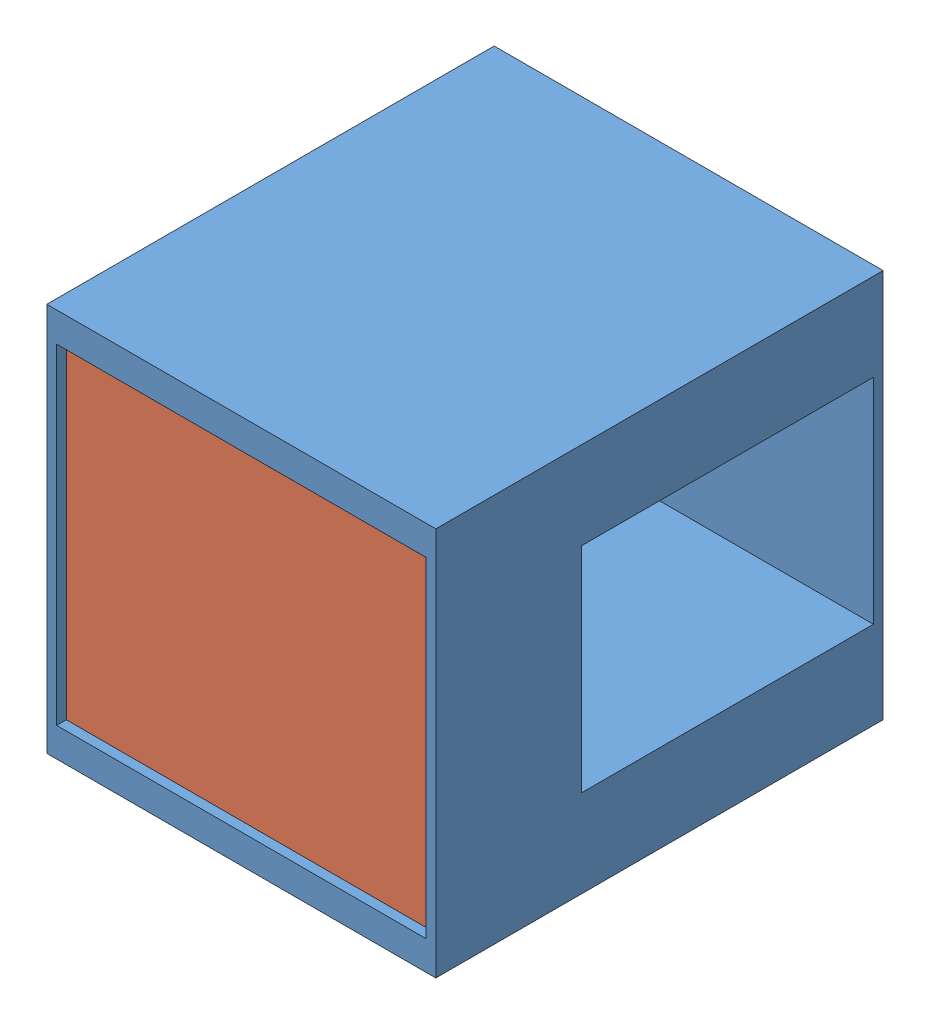
SolidWorks assembly Enclosure assem 1, configuration Default. Lengths in mm.
Overall size (101.6 101.6 116.84).
2 component instances, 2 part files, 3 mates.
Components (placement in the parent):
- Enclosure 1-1: Enclosure 1 [Default] at (-47.675 110.0742 53.7843) size (101.6 101.6 116.84)
- Enclosure top 1-1: Enclosure top 1 [Default] at (51.2011 107.5342 168.0843) x (0 -1 0) z (1 0 0) size (96.01 2.54 98.55)
Mates (geometry in assembly coordinates):
- Parallel1: parallel anti-aligned: plane of Enclosure 1-1 through (51.385 110.0742 53.7843) normal (-1 0 0); plane of Enclosure top 1-1 through (51.2011 107.5342 165.5443) normal (1 0 0)
- Coincident3: coincident anti-aligned: plane of Enclosure 1-1 through (-45.135 107.5342 56.3243) normal (0 -1 0); plane of Enclosure top 1-1 through (51.2011 107.5342 165.5443) normal (0 1 0)
- Coincident4: coincident anti-aligned: plane of Enclosure 1-1 through (-45.135 104.9942 168.0843) normal (0 0 -1); plane of Enclosure top 1-1 through (51.2011 107.5342 168.0843) normal (0 0 1)
